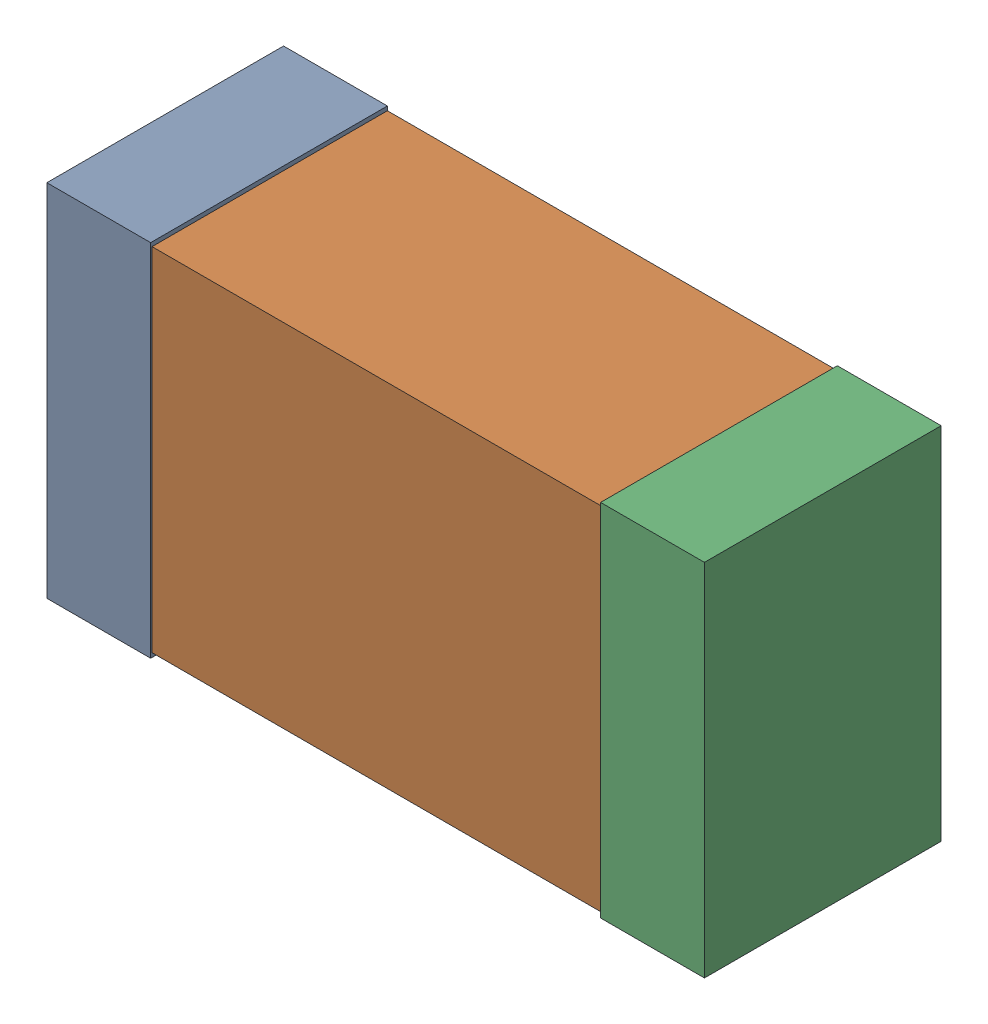
SolidWorks assembly R7Kanaloa_v2.0.0_GPIO_b, configuration Default. Lengths in mm.
Overall size (2.38 1.3 0.85).
6 component instances, 2 part files, 0 mates.
Components (placement in the parent):
- 352877648-1: 352877648 [Default] at (99.457 31.496 0) size (0.38 1.3 0.85)
  - Extruded_14-1: Extruded_14 [Default] at origin size (0.38 1.3 0.85)
- 352877392-1: 352877392 [Default] at (100.457 31.496 0) size (2.2 1.27 0.85)
  - Extruded_15-1: Extruded_15 [Default] at origin size (2.2 1.27 0.85)
- 352877648-2: 352877648 [Default] at (101.457 31.496 0) size (0.38 1.3 0.85)
  - Extruded_14-1: Extruded_14 [Default] at origin size (0.38 1.3 0.85)
